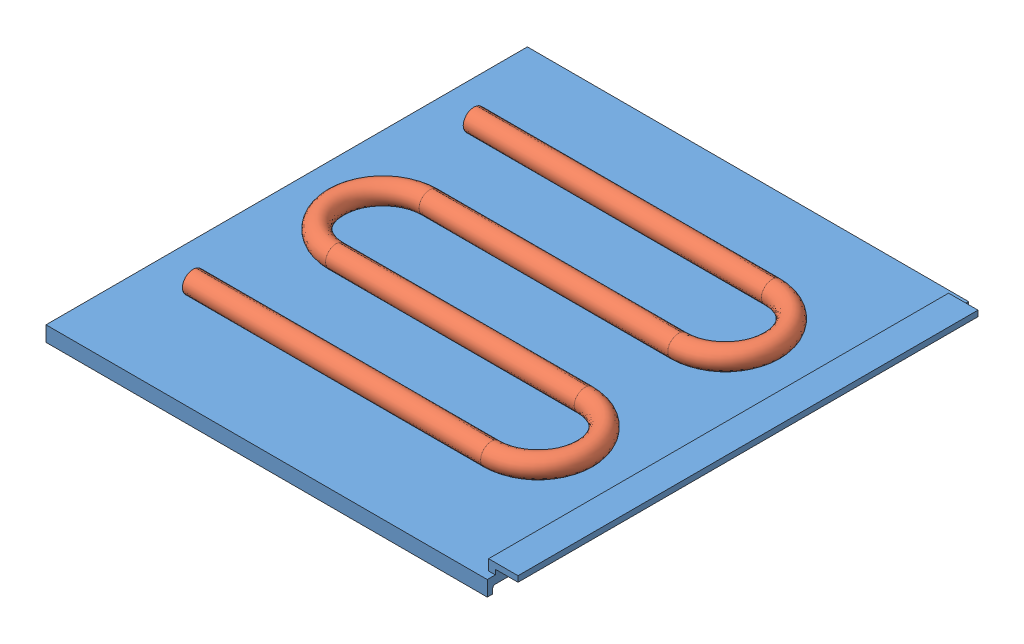
SolidWorks assembly Assem1, configuration Default. Lengths in mm.
Overall size (173.5 13.7 180).
2 component instances, 2 part files, 6 mates.
Components (placement in the parent):
- Heating Base plate-1: Heating Base plate [Default] at origin size (173.5 9.7 180)
- Heating Coil-1: Heating Coil [Default] at (0 7 -35) x (0 0 1) z (-1 0 0) size (113 8 136)
Mates (geometry in assembly coordinates):
- Coincident1: coincident aligned: plane of Heating Base plate-1 through (0 0 0) normal (0 0 1)
- Coincident2: coincident aligned: plane of Heating Base plate-1 through (0 0 0) normal (0 1 0)
- Coincident3: coincident aligned: plane of Heating Base plate-1 through (0 0 0) normal (1 0 0)
- Symmetric1: symmetric aligned: plane of Heating Base plate-1 through (-82.5 3 90) normal (0 0 1); plane of Heating Coil-1 through (-82.5 3 -90) normal (0 0 -1); plane of Heating Base plate-1 through (0 7 0) normal (0 0 1)
- Tangent1: tangent anti-aligned: plane of Heating Base plate-1 through (0 3 0) normal (0 1 0); cylinder of Heating Coil-1 through (-65 7 -52.5) axis (1 0 0) radius 4
- Symmetric2: symmetric aligned: plane of Heating Base plate-1 through (82.5 3 -90) normal (1 0 0); plane of Heating Coil-1 through (-82.5 3 -90) normal (-1 0 0); plane of Heating Base plate-1 through (0 7 -35) normal (-1 0 0)
